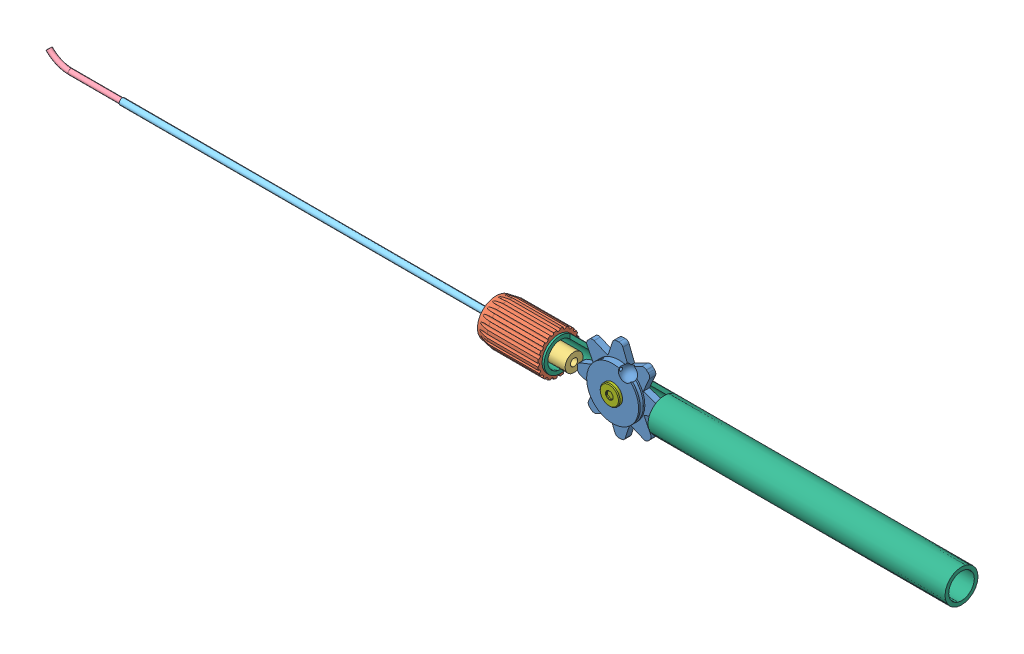
SolidWorks assembly assem_handle_ent v-2 18-Jan-2017, configuration Default. Lengths in mm.
Overall size (220.04 20.59 10.91).
7 component instances, 7 part files, 13 mates.
Components (placement in the parent):
- wheel_ent v-2 18-Jan-2017-1: wheel_ent v-2 18-Jan-2017 [Default] at (19.0216 34.2288 146.1115) x (0.999556 0.02978 0) z (0 0 1) size (20 20 3.38)
- V06_Collet_ThreadCap-1: V06_Collet_ThreadCap [Default] at (-9.7926 35.3183 146.8302) x (0 -1 0) z (0 0 1) size (10.31 15 10.31)
- Collet_1_75mmID-1: Collet_1_75mmID [Default] at (8.9574 35.3183 146.8302) x (0 -0.944085 0.329703) z (-1 0 0) size (5.98 5.98 18.75)
- nitinol notched tube v-1 17-Jan-2017-1: nitinol notched tube v-1 17-Jan-2017 [Default] at (-43.8384 35.3183 146.8302) size (18.04 3.26 1.22)
- stainless steel rod v-1 17-Jan-2017-1: stainless steel rod v-1 17-Jan-2017 [Default] at (-99.7926 35.3183 146.8302) size (90 1.47 1.47)
- wheel_handle_body v-3 18-Jan-2017-2: wheel_handle_body v-3 18-Jan-2017 [Default] at (2.2074 35.3183 146.8302) size (112.38 7.94 7.94)
- 90318A101_ULTRA LOW PROFILE TYPE 316 SS SHOULDER SCREW-1: 90318A101_ULTRA LOW PROFILE TYPE 316 SS SHOULDER SCREW [90318A101] at (19.0216 34.2288 148.4052) size (4.76 4.76 7.42)
Mates (geometry in assembly coordinates):
- Coincident3: coincident aligned: plane of V06_Collet_ThreadCap-1 through (-9.7926 35.3183 146.8302) normal (-1 0 0); plane of Collet_1_75mmID-1 through (-9.7926 35.3183 146.8302) normal (-1 0 0)
- Concentric5: concentric aligned: circle of V06_Collet_ThreadCap-1; circle of Collet_1_75mmID-1
- Coincident4: coincident anti-aligned: plane of Collet_1_75mmID-1 through (-9.7926 35.3183 146.8302) normal (-1 0 0); plane of stainless steel rod v-1 17-Jan-2017-1 through (-9.7926 35.3183 146.8302) normal (1 0 0)
- Concentric6: concentric anti-aligned: circle of V06_Collet_ThreadCap-1; circle of stainless steel rod v-1 17-Jan-2017-1
- Coincident5: coincident anti-aligned: plane of nitinol notched tube v-1 17-Jan-2017-1 through (-99.7926 35.3183 146.8302) normal (1 0 0); plane of stainless steel rod v-1 17-Jan-2017-1 through (-99.7926 35.3183 146.8302) normal (-1 0 0)
- Concentric7: concentric aligned: circle of stainless steel rod v-1 17-Jan-2017-1; circle of nitinol notched tube v-1 17-Jan-2017-1
- Coincident6: coincident anti-aligned: plane of nitinol notched tube v-1 17-Jan-2017-1 through (-99.7926 35.3183 146.8302) normal (1 0 0); plane of stainless steel rod v-1 17-Jan-2017-1 through (-99.7926 35.3183 146.8302) normal (-1 0 0)
- Coincident7: coincident anti-aligned: plane of wheel_ent v-2 18-Jan-2017-1 through (19.0216 34.2288 147.6115) normal (0 0 1); plane of 90318A101_ULTRA LOW PROFILE TYPE 316 SS SHOULDER SCREW-1 through (19.0216 31.8475 147.6115) normal (0 0 -1)
- Concentric8: concentric anti-aligned: circle of wheel_ent v-2 18-Jan-2017-1; circle of 90318A101_ULTRA LOW PROFILE TYPE 316 SS SHOULDER SCREW-1
- Coincident8: coincident anti-aligned: plane of wheel_ent v-2 18-Jan-2017-1 through (19.0532 43.2337 144.6115) normal (0 0 -1); plane of wheel_handle_body v-3 18-Jan-2017-2 through (5.7074 31.3495 144.6115) normal (0 0 1)
- Concentric9: concentric anti-aligned: circle of V06_Collet_ThreadCap-1; circle of wheel_handle_body v-3 18-Jan-2017-2
- Coincident9: coincident aligned: plane of V06_Collet_ThreadCap-1 through (-9.7926 35.3183 146.8302) normal (-1 0 0); circle of wheel_handle_body v-3 18-Jan-2017-2
- Coincident10: coincident aligned: plane of V06_Collet_ThreadCap-1 through (-9.7926 35.3183 146.8302) normal (-1 0 0); plane of Collet_1_75mmID-1 through (-9.7926 35.3183 146.8302) normal (-1 0 0)
